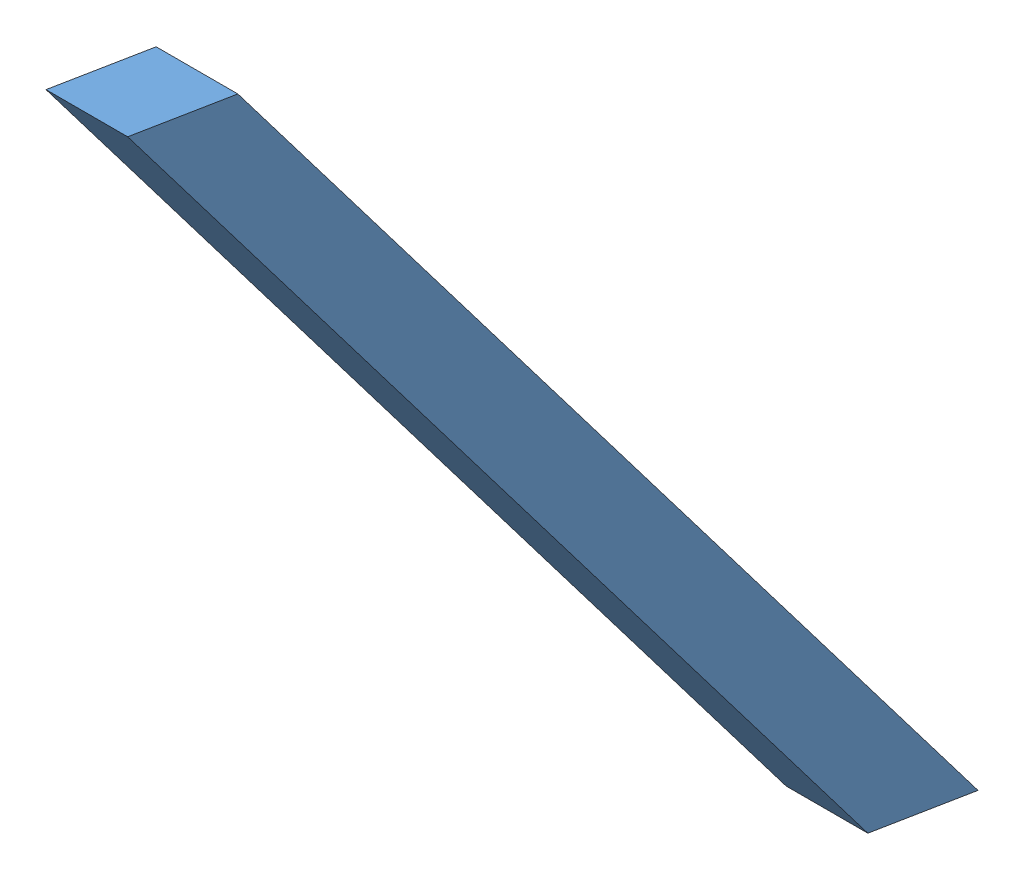
SolidWorks assembly Złożenie3, configuration Domyślna. Lengths in mm.
Overall size (405.06 842.68 593).
2 component instances, 2 part files, 2 mates.
Components (placement in the parent):
- podłoga-1: podłoga [Domyślna] at (-19.1361 -35.5206 113.8829) size (500 1 500) (hidden)
- prosty1a-1: prosty1a [Domyślna] at (270.126 -337.6575 -45.5221) x (0.9425 0.279079 0.18387) z (0 -0.550169 0.835053) size (80 986.41 80)
Mates (geometry in assembly coordinates):
- Wspólnie1: coincident: plane of podłoga-1 through (-19.1361 -34.5206 113.8829) normal (0 1 0); plane of ? through (233.5186 -34.5206 -164.1672) normal (0 -1 0)
- Wspólnie2: coincident: line of assembly; line of assembly; line of podłoga-1 through (-276.186 -34.5206 250) axis (1 0 0); line of prosty1a-1 through (-81.5591 -34.5206 250) axis (1 0 0)
